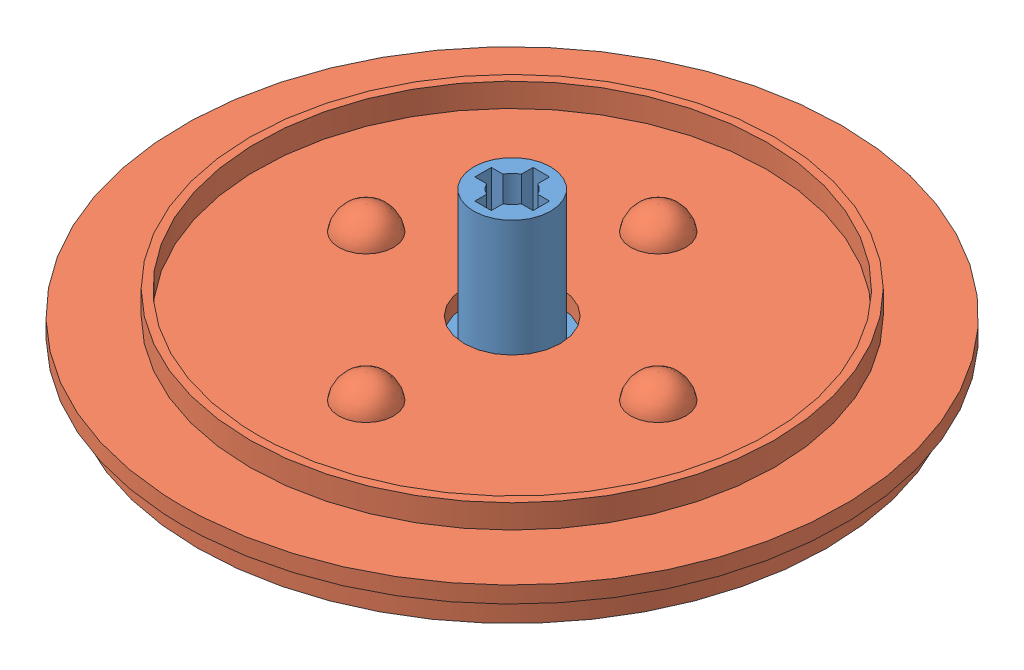
SolidWorks assembly chopper-adapters Assembly, configuration Default. Lengths in mm.
Overall size (168.9 195.66 120).
2 component instances, 2 part files, 2 mates.
Components (placement in the parent):
- chopper motor adapter-2: chopper motor adapter [Default] at (547.9662 557.6529 609.4026) x (1 0 0) z (0 0 -1) size (158.03 195.66 39)
- chopper jar base adapter-2: chopper jar base adapter [Default] at (547.9662 557.6529 609.4026) size (120 14.3 120)
Mates (geometry in assembly coordinates):
- Coincident1: coincident anti-aligned: plane of chopper motor adapter-2 through (547.9662 557.6529 609.4026) normal (0 1 0); plane of chopper jar base adapter-2 through (547.9662 557.6529 609.4026) normal (0 -1 0)
- Concentric1: concentric aligned: cylinder of chopper motor adapter-2 through (547.9662 580.6529 609.4026) axis (0 -1 0) radius 7; cylinder of chopper jar base adapter-2 through (547.9662 560.6529 609.4026) axis (0 -1 0) radius 8.75
